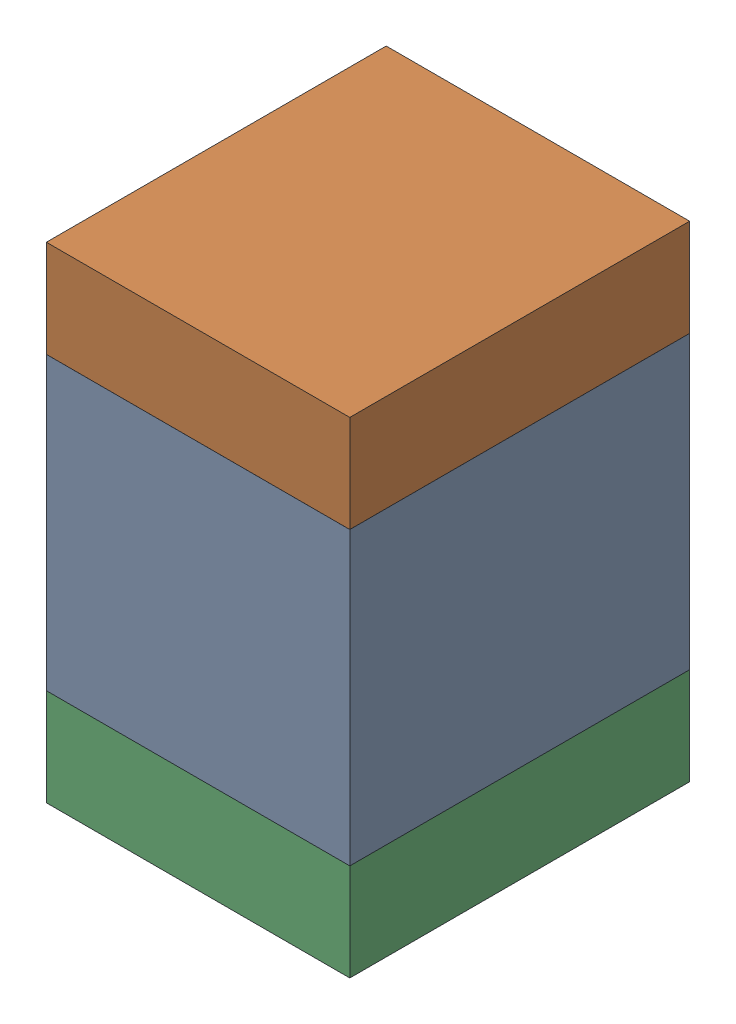
SolidWorks assembly C33, configuration ﾃﾞﾌｫﾙﾄ. Lengths in mm.
Overall size (1.25 2 1.4).
6 component instances, 2 part files, 0 mates.
Components (placement in the parent):
- 689259472-1: 689259472 [ﾃﾞﾌｫﾙﾄ] at (79.75 22 0) size (1.25 1.2 1.4)
  - Extruded_9-1: Extruded_9 [ﾃﾞﾌｫﾙﾄ] at origin size (1.25 1.2 1.4)
- 689259336-1: 689259336 [ﾃﾞﾌｫﾙﾄ] at (79.75 22.8001 0) size (1.25 0.4 1.4)
  - Extruded_8-1: Extruded_8 [ﾃﾞﾌｫﾙﾄ] at origin size (1.25 0.4 1.4)
- 689259336-2: 689259336 [ﾃﾞﾌｫﾙﾄ] at (79.75 21.2001 0) size (1.25 0.4 1.4)
  - Extruded_8-1: Extruded_8 [ﾃﾞﾌｫﾙﾄ] at origin size (1.25 0.4 1.4)
